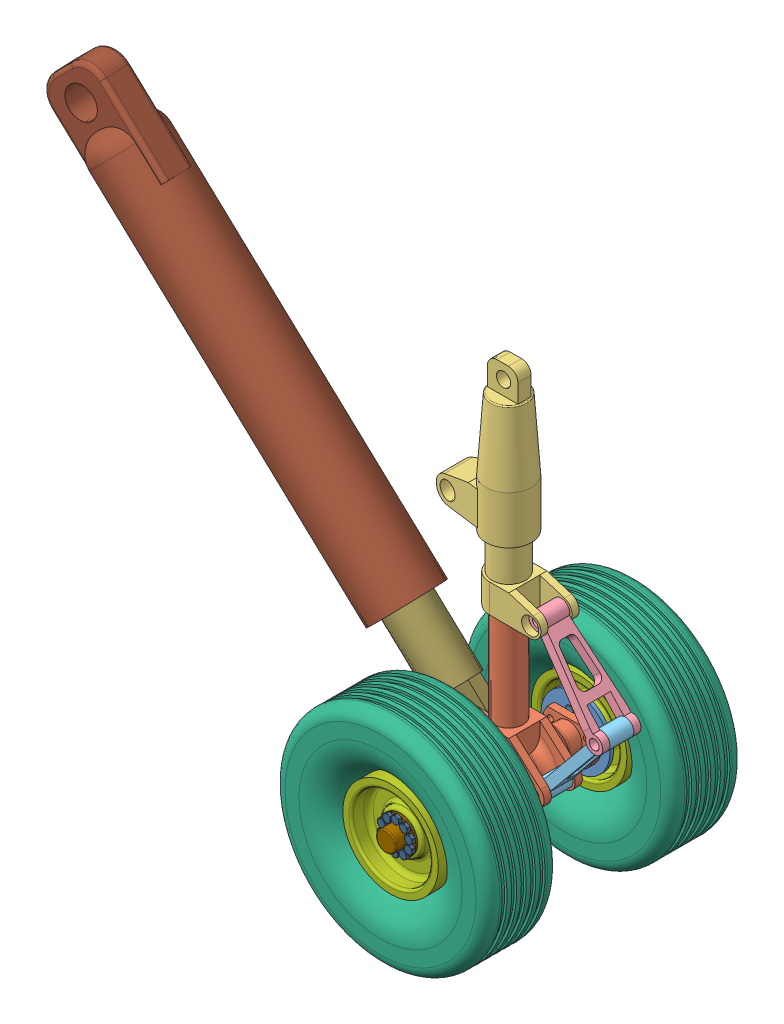
SolidWorks assembly Assem4, configuration Default. Lengths in mm.
Overall size (2337.01 2337.08 1073.8).
36 component instances, 12 part files, 41 mates.
Components (placement in the parent):
- Disc Plate-1: Disc Plate [Default] at (0 0 287.5) x (0.61021 -0.79224 0) z (0 0 1) size (289.01 289.01 15)
- 1586503671768_First Part Telestropic strut 4aaa-1: 1586503671768_First Part Telestropic strut 4aaa [Default] at origin size (413.8 1023.16 560)
- leg-1: leg [Default] at (0 725.3108 0) x (0 0 1) z (0 1 0) size (190 465 888.17)
- Linkage 1-1: Linkage 1 [Default] at (170 650.3108 -80) x (0.670616 -0.741805 0) z (0 0 1) size (472 72 160)
- Linkage 2-1: Linkage 2 [Default] at (438.2464 353.5889 0) x (-0.636263 -0.771472 0) z (0 0 1) size (472 72 100)
- Wheel-1: Wheel [Default] at (0 0 536.8987) x (0 0 -1) z (0.997027 -0.077052 0) size (300 900 900)
- Wheel hub-1: Wheel hub [Default] at (0 0 495) x (0 0 -1) z (0.336028 0.941852 0) size (200 400 400)
- Shaft-1: Shaft [Default] x (-0.961546 -0.274643 0) z (0 0 1) size (78 78 1000)
- Disc Plate-2: Disc Plate [Default] at (0 0 -287.5) x (-0.61021 0.79224 0) z (0 0 -1) size (289.01 289.01 15)
- Wheel hub-2: Wheel hub [Default] at (0 0 -495) x (0 0 1) z (-0.336028 -0.941852 0) size (200 400 400)
- Wheel-2: Wheel [Default] at (0 0 -536.8987) x (0 0 1) z (-0.997027 0.077052 0) size (300 900 900)
- End cap-1: End cap [Default] at (0 0 465) x (-0.825459 -0.564462 0) z (0 0 -1) size (150 150 60)
- End cap-2: End cap [Default] at (0 0 -465) x (0.825459 0.564462 0) z (0 0 1) size (150 150 60)
- heavy hex bolt_ai-8: heavy hex bolt_ai [HHBOLT 0.7500-16x0.75x0.75-N] at (-33.8677 49.5276 478.3096) x (0 0 -1) z (1 0 0) size (32.36 36.66 31.75)
- heavy hex bolt_ai-9: heavy hex bolt_ai [HHBOLT 0.7500-16x0.75x0.75-N] at (1.712 59.9756 478.3096) x (0 0 -1) z (0.990963 0.134138 0) size (32.36 36.66 31.75)
- heavy hex bolt_ai-10: heavy hex bolt_ai [HHBOLT 0.7500-16x0.75x0.75-N] at (36.6378 47.515 478.3096) x (0 0 -1) z (1 0 0) size (32.36 36.66 31.75)
- heavy hex bolt_ai-12: heavy hex bolt_ai [HHBOLT 0.7500-16x0.75x0.75-N] at (57.5692 16.9052 478.3096) x (0 0 -1) z (1 0 0) size (32.36 36.66 31.75)
- heavy hex bolt_ai-11: heavy hex bolt_ai [HHBOLT 0.7500-16x0.75x0.75-N] at (56.5111 -20.1617 478.3096) x (0 0 -1) z (1 0 0) size (32.36 36.66 31.75)
- heavy hex bolt_ai-13: heavy hex bolt_ai [HHBOLT 0.7500-16x0.75x0.75-N] at (33.8677 -49.5276 478.3096) x (0 0 -1) z (1 0 0) size (32.36 36.66 31.75)
- heavy hex bolt_ai-7: heavy hex bolt_ai [HHBOLT 0.7500-16x0.75x0.75-N] at (-1.712 -59.9756 478.3096) x (0 0 -1) z (1 0 0) size (32.36 36.66 31.75)
- heavy hex bolt_ai-14: heavy hex bolt_ai [HHBOLT 0.7500-16x0.75x0.75-N] at (-36.6378 -47.515 478.3096) x (0 0 -1) z (1 0 0) size (32.36 36.66 31.75)
- heavy hex bolt_ai-15: heavy hex bolt_ai [HHBOLT 0.7500-16x0.75x0.75-N] at (-57.5692 -16.9052 478.3096) x (0 0 -1) z (1 0 0) size (32.36 36.66 31.75)
- heavy hex bolt_ai-16: heavy hex bolt_ai [HHBOLT 0.7500-16x0.75x0.75-N] at (-56.5111 20.1617 478.3096) x (0 0 -1) z (1 0 0) size (32.36 36.66 31.75)
- heavy hex bolt_ai-17: heavy hex bolt_ai [HHBOLT 0.7500-16x0.75x0.75-N] at (-33.8677 49.5276 -478.3096) x (0 0 1) z (-1 0 0) size (32.36 36.66 31.75)
- heavy hex bolt_ai-18: heavy hex bolt_ai [HHBOLT 0.7500-16x0.75x0.75-N] at (1.712 59.9756 -478.3096) x (0 0 1) z (-0.990963 -0.134138 0) size (32.36 36.66 31.75)
- heavy hex bolt_ai-19: heavy hex bolt_ai [HHBOLT 0.7500-16x0.75x0.75-N] at (36.6378 47.515 -478.3096) x (0 0 1) z (-1 0 0) size (32.36 36.66 31.75)
- heavy hex bolt_ai-20: heavy hex bolt_ai [HHBOLT 0.7500-16x0.75x0.75-N] at (57.5692 16.9052 -478.3096) x (0 0 1) z (-1 0 0) size (32.36 36.66 31.75)
- heavy hex bolt_ai-21: heavy hex bolt_ai [HHBOLT 0.7500-16x0.75x0.75-N] at (56.5111 -20.1617 -478.3096) x (0 0 1) z (-1 0 0) size (32.36 36.66 31.75)
- heavy hex bolt_ai-22: heavy hex bolt_ai [HHBOLT 0.7500-16x0.75x0.75-N] at (33.8677 -49.5276 -478.3096) x (0 0 1) z (-1 0 0) size (32.36 36.66 31.75)
- heavy hex bolt_ai-23: heavy hex bolt_ai [HHBOLT 0.7500-16x0.75x0.75-N] at (-1.712 -59.9756 -478.3096) x (0 0 1) z (-1 0 0) size (32.36 36.66 31.75)
- heavy hex bolt_ai-24: heavy hex bolt_ai [HHBOLT 0.7500-16x0.75x0.75-N] at (-36.6378 -47.515 -478.3096) x (0 0 1) z (-1 0 0) size (32.36 36.66 31.75)
- heavy hex bolt_ai-25: heavy hex bolt_ai [HHBOLT 0.7500-16x0.75x0.75-N] at (-57.5692 -16.9052 -478.3096) x (0 0 1) z (-1 0 0) size (32.36 36.66 31.75)
- heavy hex bolt_ai-26: heavy hex bolt_ai [HHBOLT 0.7500-16x0.75x0.75-N] at (-56.5111 20.1617 -478.3096) x (0 0 1) z (-1 0 0) size (32.36 36.66 31.75)
- Assem1-1: Assem1 [Default] at (-1113.1949 1131.6399 10.1684) x (-0.705871 0.707843 0.026556) z (0.067456 0.029854 0.997276) size (2356.89 282.18 282.18)
  - Part1-1: Part1 [Default] at (-27.5678 1.4874 37.8125) size (1887.87 282.18 282.18)
  - Part2-1: Part2 [Default] at (-586.2219 7.2296 32.4431) x (-0.001063 -0.999951 -0.009796) z (0.999999 -0.001064 0.000044) size (181.47 181.47 1649.7)
Mates (geometry in assembly coordinates):
- Coincident1: coincident aligned: plane of 1586503671768_First Part Telestropic strut 4aaa-1 through (0 0 0) normal (0 0 1); plane of assembly through (0 0 0) normal (0 0 1)
- Coincident2: coincident aligned: plane of 1586503671768_First Part Telestropic strut 4aaa-1 through (0 0 0) normal (0 1 0); plane of assembly through (0 0 0) normal (0 1 0)
- Coincident3: coincident aligned: plane of 1586503671768_First Part Telestropic strut 4aaa-1 through (0 0 0) normal (1 0 0); plane of assembly through (0 0 0) normal (1 0 0)
- Concentric1: concentric aligned: cylinder of Wheel-1 through (0 0 236.8987) axis (0 0 1) radius 200; cylinder of Wheel hub-1 through (0 0 455) axis (0 0 1) radius 200.001
- Concentric2: concentric anti-aligned: cylinder of 1586503671768_First Part Telestropic strut 4aaa-1 through (0 0 250) axis (0 0 -1) radius 57.5; cylinder of Wheel hub-1 through (0 0 455) axis (0 0 1) radius 200.001
- Coincident4: coincident aligned: circle of Wheel-1; circle of Wheel hub-1
- Concentric3: concentric anti-aligned: cylinder of Disc Plate-1 through (0 0 280) axis (0 0 1) radius 40; cylinder of 1586503671768_First Part Telestropic strut 4aaa-1 through (0 0 250) axis (0 0 -1) radius 57.5
- Concentric4: concentric aligned: cylinder of 1586503671768_First Part Telestropic strut 4aaa-1 through (0 0 250) axis (0 0 -1) radius 40; cylinder of Shaft-1 through (0 0 500) axis (0 0 -1) radius 39
- Width1: width aligned: plane of Shaft-1 through (0 0 -500) normal (0 0 -1); plane of 1586503671768_First Part Telestropic strut 4aaa-1 through (0 0 500) normal (0 0 1); plane of Shaft-1 through (0 197 -80) normal (0 0 -1); plane of 1586503671768_First Part Telestropic strut 4aaa-1 through (0 197 80) normal (0 0 1)
- Concentric5: concentric aligned: cylinder of 1586503671768_First Part Telestropic strut 4aaa-1 through (0 897 0) axis (0 -1 0) radius 60; cylinder of leg-1 through (0 1205.3108 0) axis (0 -1 0) radius 60
- Coincident5: coincident aligned: plane of 1586503671768_First Part Telestropic strut 4aaa-1 through (0 197 -80) normal (0 0 -1); plane of leg-1 through (0 725.3108 -80) normal (0 0 -1)
- Concentric6: concentric aligned: cylinder of leg-1 through (170 650.3108 80) axis (0 0 -1) radius 36; cylinder of Linkage 1-1 through (170 650.3108 80) axis (0 0 -1) radius 21
- Coincident6: coincident anti-aligned: plane of leg-1 through (80 605.3108 -50) normal (0 0 1); plane of Linkage 1-1 through (143.295 626.1687 -50) normal (0 0 -1)
- Concentric7: concentric aligned: cylinder of Linkage 1-1 through (438.2464 353.5889 80) axis (0 0 -1) radius 21; cylinder of Linkage 2-1 through (438.2464 353.5889 50) axis (0 0 -1) radius 24
- Coincident7: coincident anti-aligned: plane of Linkage 1-1 through (143.295 626.1687 -50) normal (0 0 1); plane of Linkage 2-1 through (183.7412 45 -50) normal (0 0 -1)
- Concentric8: concentric aligned: cylinder of 1586503671768_First Part Telestropic strut 4aaa-1 through (183.7412 45 -50) axis (0 0 -1) radius 24; cylinder of Linkage 2-1 through (183.7412 45 50) axis (0 0 -1) radius 36
- Concentric9: concentric aligned: cylinder of Shaft-1 through (0 0 500) axis (0 0 -1) radius 39; cylinder of End cap-1 through (0 0 515) axis (0 0 -1) radius 41.655
- Coincident10: coincident anti-aligned: plane of Disc Plate-1 through (0 0 280) normal (0 0 -1); plane of 1586503671768_First Part Telestropic strut 4aaa-1 through (0 0 280) normal (0 0 1)
- Coincident11: coincident anti-aligned: plane of Disc Plate-1 through (0 0 295) normal (0 0 1); plane of Wheel hub-1 through (-164.825 58.8053 295) normal (0 0 -1)
- Concentric10: concentric aligned: cylinder of Wheel hub-1 through (36.6378 47.515 295) axis (0 0 1) radius 10; cylinder of End cap-1 through (36.6378 47.515 455) axis (0 0 1) radius 10
- Coincident12: coincident anti-aligned: plane of Wheel hub-1 through (-70.6389 25.2021 455) normal (0 0 1); plane of End cap-1 through (0 0 455) normal (0 0 -1)
- Concentric421: concentric aligned: cylinder of End cap-1 through (-33.8677 49.5276 455) axis (0 0 1) radius 10; cylinder of heavy hex bolt_ai-8 through (-33.8677 49.5276 478.3096) axis (0 0 1) radius 9.525
- Coincident431: coincident anti-aligned: plane of End cap-1 through (0 0 465) normal (0 0 1); plane of heavy hex bolt_ai-8 through (-33.8677 67.8584 465) normal (0 0 -1)
- Concentric431: concentric aligned: cylinder of End cap-1 through (1.712 59.9756 455) axis (0 0 1) radius 10; cylinder of heavy hex bolt_ai-9 through (1.712 59.9756 478.3096) axis (0 0 1) radius 9.525
- Coincident441: coincident anti-aligned: plane of End cap-1 through (0 0 465) normal (0 0 1); plane of heavy hex bolt_ai-9 through (-0.7469 78.1408 465) normal (0 0 -1)
- Concentric441: concentric aligned: cylinder of End cap-1 through (36.6378 47.515 455) axis (0 0 1) radius 10; cylinder of heavy hex bolt_ai-10 through (36.6378 47.515 478.3096) axis (0 0 1) radius 9.525
- Coincident451: coincident anti-aligned: plane of End cap-1 through (0 0 465) normal (0 0 1); plane of heavy hex bolt_ai-10 through (36.6378 65.8458 465) normal (0 0 -1)
- Concentric451: concentric aligned: cylinder of End cap-1 through (57.5692 16.9052 455) axis (0 0 1) radius 10; cylinder of heavy hex bolt_ai-12 through (57.5692 16.9052 478.3096) axis (0 0 1) radius 9.525
- Coincident461: coincident anti-aligned: plane of End cap-1 through (0 0 465) normal (0 0 1); plane of heavy hex bolt_ai-12 through (57.5692 35.2361 465) normal (0 0 -1)
- Concentric461: concentric aligned: cylinder of End cap-1 through (56.5111 -20.1617 455) axis (0 0 1) radius 10; cylinder of heavy hex bolt_ai-11 through (56.5111 -20.1617 478.3096) axis (0 0 1) radius 9.525
- Coincident471: coincident anti-aligned: plane of End cap-1 through (0 0 465) normal (0 0 1); plane of heavy hex bolt_ai-11 through (56.5111 -1.8308 465) normal (0 0 -1)
- Concentric471: concentric aligned: cylinder of End cap-1 through (33.8677 -49.5276 455) axis (0 0 1) radius 10; cylinder of heavy hex bolt_ai-13 through (33.8677 -49.5276 478.3096) axis (0 0 1) radius 9.525
- Coincident481: coincident anti-aligned: plane of End cap-1 through (0 0 465) normal (0 0 1); plane of heavy hex bolt_ai-13 through (33.8677 -31.1967 465) normal (0 0 -1)
- Concentric481: concentric aligned: cylinder of End cap-1 through (-1.712 -59.9756 455) axis (0 0 1) radius 10; cylinder of heavy hex bolt_ai-7 through (-1.712 -59.9756 478.3096) axis (0 0 1) radius 9.525
- Coincident491: coincident anti-aligned: plane of End cap-1 through (0 0 465) normal (0 0 1); plane of heavy hex bolt_ai-7 through (-1.712 -41.6447 465) normal (0 0 -1)
- Concentric491: concentric aligned: cylinder of End cap-1 through (-36.6378 -47.515 455) axis (0 0 1) radius 10; cylinder of heavy hex bolt_ai-14 through (-36.6378 -47.515 478.3096) axis (0 0 1) radius 9.525
- Coincident501: coincident anti-aligned: plane of End cap-1 through (0 0 465) normal (0 0 1); plane of heavy hex bolt_ai-14 through (-36.6378 -29.1841 465) normal (0 0 -1)
- Concentric501: concentric aligned: cylinder of End cap-1 through (-57.5692 -16.9052 455) axis (0 0 1) radius 10; cylinder of heavy hex bolt_ai-15 through (-57.5692 -16.9052 478.3096) axis (0 0 1) radius 9.525
- Coincident511: coincident anti-aligned: plane of End cap-1 through (0 0 465) normal (0 0 1); plane of heavy hex bolt_ai-15 through (-57.5692 1.4256 465) normal (0 0 -1)
- Concentric511: concentric aligned: cylinder of End cap-1 through (-56.5111 20.1617 455) axis (0 0 1) radius 10; cylinder of heavy hex bolt_ai-16 through (-56.5111 20.1617 478.3096) axis (0 0 1) radius 9.525
- Coincident521: coincident anti-aligned: plane of End cap-1 through (0 0 465) normal (0 0 1); plane of heavy hex bolt_ai-16 through (-56.5111 38.4926 465) normal (0 0 -1)
